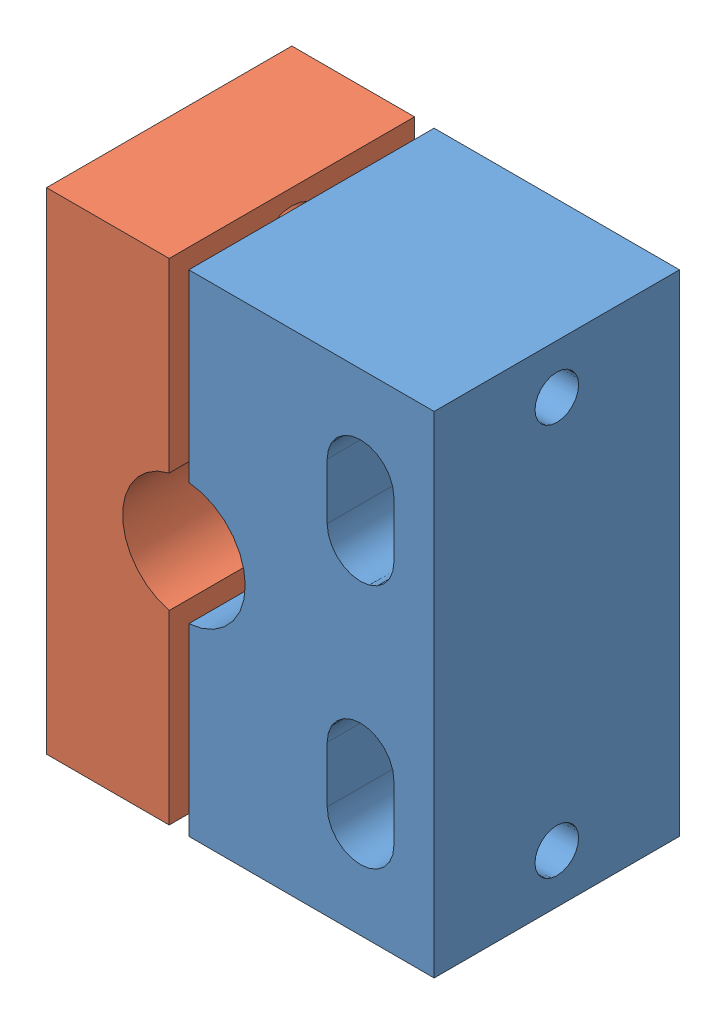
SolidWorks assembly coax_clamp_assem, configuration Default. Lengths in mm.
Overall size (20.07 25.4 12.7).
2 component instances, 2 part files, 3 mates.
Components (placement in the parent):
- coax_clamp_base-1: coax_clamp_base [Default] at origin size (12.7 25.4 12.7)
- coax_clamp_top-1: coax_clamp_top [Default] at (-10.541 0 12.7) x (-1 0 0) z (0 0 -1) size (6.35 25.4 12.7)
Mates (geometry in assembly coordinates):
- Concentric1: concentric: cylinder of coax_clamp_base-1 through (-6.604 0 0) axis (0 0 1) radius 3.175; cylinder of coax_clamp_top-1 through (-6.604 0 12.7) axis (0 0 -1) radius 3.175
- Parallel1: parallel: plane of coax_clamp_base-1 through (-6.35 12.7 12.7) normal (-1 0 0); plane of coax_clamp_top-1 through (-7.366 12.7 0) normal (1 0 0)
- Coincident2: coincident aligned: plane of coax_clamp_base-1 through (0 0 0) normal (0 0 -1); plane of coax_clamp_top-1 through (-10.541 0 0) normal (0 0 -1)
